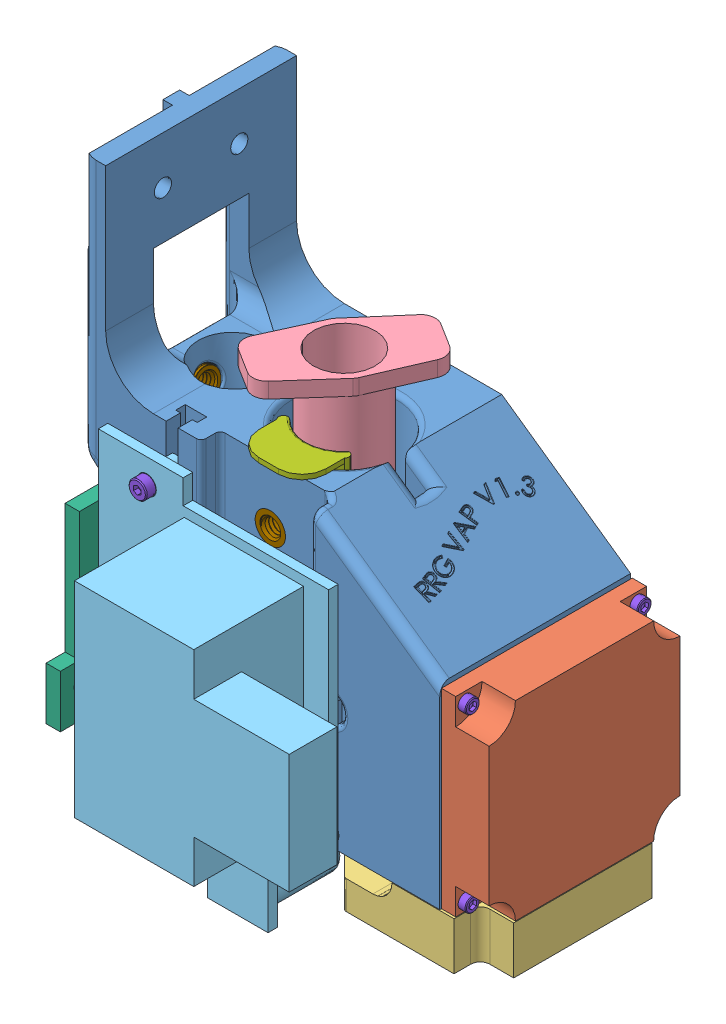
SolidWorks assembly nozzle5_assembly, configuration Default. Lengths in mm.
Overall size (89.5 117.49 68.04).
22 component instances, 9 part files, 46 mates.
Components (placement in the parent):
- nozzle5-1: nozzle5 [Default] at (-8.7686 3.4195 32.0413) size (79.5 100 40.07)
- fan-1: fan [Default] at (61.2314 3.4195 71.6933) x (0 0 -1) z (0 -1 0) size (40 10 40)
- fan_flow-1: fan_flow [Default] at (71.2314 -6.7344 72.0413) x (-1 0 0) z (0 0 -1) size (42.01 10.01 40)
- syringe_OG-1: syringe_OG [Default] at (23.2314 2.7419 54.0413) x (0.847098 0 0.531436) z (-0.531436 0 0.847098) size (15.68 90.3 30.7)
- sensing_board-1: sensing_board [Default] at (-5.6177 59.601 74.7313) x (0 -1 0) z (-1 0 0) size (73.67 39.39 63)
- heater_board-1: heater_board [Default] at (-11.7686 40.4195 78.5413) x (0 0 -1) z (-1 0 0) size (39 38 6)
- syringe_clamp_V2-1: syringe_clamp_V2 [Default] at (23.2314 13.4195 54.0413) x (0.707107 0 0.707107) z (-0.707107 0 0.707107) size (15.16 51.07 15.16)
- socket head cap screw_am-5: socket head cap screw_am [B18.3.1M - 2.5 x 0.45 x 10 Hex SHCS -- 10NHX] at (-17.2686 35.4195 68.0413) size (12.5 4.5 4.5)
- socket head cap screw_am-6: socket head cap screw_am [B18.3.1M - 2.5 x 0.45 x 10 Hex SHCS -- 10NHX] at (-17.2686 9.0195 53.1413) size (12.5 4.5 4.5)
- socket head cap screw_am-8: socket head cap screw_am [B18.3.1M - 2 x 0.4 x 10 Hex SHCS -- 10NHX] at (4.5423 54.521 78.7313) x (0 0 -1) z (1 0 0) size (12 3.8 3.8)
- socket head cap screw_am-9: socket head cap screw_am [B18.3.1M - 2 x 0.4 x 10 Hex SHCS -- 10NHX] at (4.5423 6.261 78.7313) x (0 0 -1) z (1 0 0) size (12 3.8 3.8)
- socket head cap screw_am-10: socket head cap screw_am [B18.3.1M - 2 x 0.4 x 10 Hex SHCS -- 10NHX] at (37.5623 6.261 78.7313) x (0 0 -1) z (1 0 0) size (12 3.8 3.8)
- 93365A140_HEAT-SET INSERTS FOR PLASTICS-1: 93365A140_HEAT-SET INSERTS FOR PLASTICS [93365A140] at (-10.362 55.4311 53.7913) x (0.178209 -0.977712 0.110994) z (0.019903 -0.109195 -0.993821) size (6.35 5.19 6.35)
- 93365A140_HEAT-SET INSERTS FOR PLASTICS-2: 93365A140_HEAT-SET INSERTS FOR PLASTICS [93365A140] at (-8.1205 43.1337 53.7913) x (0.178209 -0.977712 0.110994) z (0.019903 -0.109195 -0.993821) size (6.35 5.19 6.35)
- 93365A140_HEAT-SET INSERTS FOR PLASTICS-4: 93365A140_HEAT-SET INSERTS FOR PLASTICS [93365A140] at (21.7314 20.9195 68.0413) x (-0.923728 -0.383049 0) z (-0.383049 0.923728 0) size (6.35 5.19 6.35)
- 93365A140_HEAT-SET INSERTS FOR PLASTICS-5: 93365A140_HEAT-SET INSERTS FOR PLASTICS [93365A140] at (21.7314 50.9195 68.0413) x (-0.980674 -0.195651 0) z (-0.195651 0.980674 0) size (6.35 5.19 6.35)
- socket head cap screw_am-12: socket head cap screw_am [B18.3.1M - 1.6 x 0.35 x 10 Hex SHCS -- 10NHX] at (54.2314 -8.3344 69.0413) x (0 1 0) z (0 0 1) size (11.6 3 3)
- socket head cap screw_am-13: socket head cap screw_am [B18.3.1M - 1.6 x 0.35 x 10 Hex SHCS -- 10NHX] at (54.2314 -8.3344 35.0413) x (0 1 0) z (0 0 1) size (11.6 3 3)
- socket head cap screw_am-14: socket head cap screw_am [B18.3.1M - 1.6 x 0.35 x 10 Hex SHCS -- 10NHX] at (65.8314 41.4195 69.6933) x (-1 0 0) z (0 0.924225 0.381849) size (11.6 3 3)
- socket head cap screw_am-15: socket head cap screw_am [B18.3.1M - 1.6 x 0.35 x 10 Hex SHCS -- 10NHX] at (65.8314 41.4195 33.6933) x (-1 0 0) z (0 0.924225 0.381849) size (11.6 3 3)
- socket head cap screw_am-16: socket head cap screw_am [B18.3.1M - 1.6 x 0.35 x 10 Hex SHCS -- 10NHX] at (65.8314 5.4195 69.6933) x (-1 0 0) z (0 0.924225 0.381849) size (11.6 3 3)
- socket head cap screw_am-17: socket head cap screw_am [B18.3.1M - 1.6 x 0.35 x 10 Hex SHCS -- 10NHX] at (65.8314 5.4195 33.6933) x (-1 0 0) z (0 0.924225 0.381849) size (11.6 3 3)
Mates (geometry in assembly coordinates):
- Concentric1: concentric: cylinder of nozzle5-1 through (23.2314 -27.6932 54.0413) axis (0 1 0) radius 11; cylinder of syringe_OG-1 through (23.2314 74.0419 54.0413) axis (0 -1 0) radius 7.6
- Coincident2: coincident: plane of nozzle5-1 through (-8.7686 3.4195 72.0413) normal (0 -1 0); plane of fan-1 through (71.2314 3.4195 71.6933) normal (0 -1 0)
- Coincident4: coincident: plane of fan-1 through (71.2314 3.4195 71.6933) normal (1 0 0); plane of fan_flow-1 through (71.2314 -6.7344 32.0413) normal (1 0 0)
- Concentric2: concentric: cylinder of nozzle5-1 through (54.2314 13.4195 69.0413) axis (0 -1 0) radius 1.1; cylinder of fan_flow-1 through (54.2314 -6.7344 69.0413) axis (0 -1 0) radius 1.1
- Parallel1: parallel: plane of nozzle5-1 through (-8.7686 3.4195 72.0413) normal (0 0 1); plane of sensing_board-1 through (-5.6177 59.601 74.7313) normal (0 0 -1)
- Parallel2: parallel: plane of nozzle5-1 through (-8.7686 3.4195 72.0413) normal (-1 0 0); plane of sensing_board-1 through (-5.6177 59.601 76.7313) normal (-1 0 0)
- Distance1: distance = 4 mm: plane of sensing_board-1 through (23.5976 -8.9867 60.3413) normal (0 0 -1); cylinder of syringe_OG-1 through (23.2314 -13.0081 54.0413) axis (0 1 0) radius 2.3
- Parallel3: parallel: plane of nozzle5-1 through (-8.7686 3.4195 72.0413) normal (-1 0 0); plane of heater_board-1 through (-11.7686 40.4195 78.5413) normal (1 0 0)
- Concentric3: concentric: cylinder of nozzle5-1 through (23.2314 -27.6932 54.0413) axis (0 1 0) radius 11; cylinder of syringe_clamp_V2-1 through (23.2314 63.4195 54.0413) axis (0 -1 0) radius 10
- Coincident12: coincident: plane of nozzle5-1 through (61.2314 3.4195 72.0413) normal (1 0 0); plane of fan-1 through (61.2314 3.4195 71.6933) normal (-1 0 0)
- Concentric4: concentric: cylinder of nozzle5-1 through (-0.7686 35.4195 68.0413) axis (-1 0 0) radius 1.5; cylinder of heater_board-1 through (-11.7686 35.4195 68.0413) axis (-1 0 0) radius 2
- Concentric5: concentric: cylinder of nozzle5-1 through (-0.7686 9.0195 53.1413) axis (-1 0 0) radius 1.5; cylinder of heater_board-1 through (-11.7686 9.0195 53.1413) axis (-1 0 0) radius 2
- Coincident13: coincident: plane of nozzle5-1 through (-8.7686 3.4195 72.0413) normal (-1 0 0); plane of heater_board-1 through (-8.7686 9.0195 53.1413) normal (1 0 0)
- Coincident14: coincident: plane of nozzle5-1 through (-8.7686 63.4195 72.0413) normal (0 1 0); plane of syringe_clamp_V2-1 through (23.2314 63.4195 54.0413) normal (0 -1 0)
- Parallel4: parallel: plane of nozzle5-1 through (-8.7686 3.4195 68.0413) normal (0 0 1); plane of syringe_clamp_V2-1 through (23.2314 64.4195 69.9291) normal (0 0 1)
- Concentric6: concentric: cylinder of heater_board-1 through (-11.7686 35.4195 68.0413) axis (-1 0 0) radius 2; cylinder of socket head cap screw_am-5 through (-49.0186 35.4195 68.0413) axis (-1 0 0) radius 2.25
- Coincident16: coincident: plane of heater_board-1 through (-14.7686 40.4195 78.5413) normal (-1 0 0); plane of socket head cap screw_am-5 through (-14.7686 37.6695 68.0413) normal (1 0 0)
- Concentric7: concentric: cylinder of heater_board-1 through (-11.7686 9.0195 53.1413) axis (-1 0 0) radius 2; cylinder of socket head cap screw_am-6 through (-49.0186 9.0195 53.1413) axis (-1 0 0) radius 2.25
- Coincident17: coincident: plane of heater_board-1 through (-14.7686 40.4195 78.5413) normal (-1 0 0); plane of socket head cap screw_am-6 through (-14.7686 11.2695 53.1413) normal (1 0 0)
- Concentric8: concentric: cylinder of sensing_board-1 through (4.5423 54.521 76.7313) axis (0 0 -1) radius 2; cylinder of socket head cap screw_am-8 through (4.5423 54.521 110.4813) axis (0 0 1) radius 1.9
- Coincident18: coincident: plane of sensing_board-1 through (-5.6177 59.601 76.7313) normal (0 0 1); plane of socket head cap screw_am-8 through (4.5423 56.421 76.7313) normal (0 0 -1)
- Concentric9: concentric: cylinder of sensing_board-1 through (4.5423 6.261 76.7313) axis (0 0 -1) radius 2; cylinder of socket head cap screw_am-9 through (4.5423 6.261 110.4813) axis (0 0 1) radius 1.9
- Coincident19: coincident: plane of sensing_board-1 through (-5.6177 59.601 76.7313) normal (0 0 1); plane of socket head cap screw_am-9 through (4.5423 8.161 76.7313) normal (0 0 -1)
- Concentric10: concentric: cylinder of sensing_board-1 through (37.5623 6.261 76.7313) axis (0 0 -1) radius 2; cylinder of socket head cap screw_am-10 through (37.5623 6.261 110.4813) axis (0 0 1) radius 1.9
- Coincident20: coincident: plane of sensing_board-1 through (-5.6177 59.601 76.7313) normal (0 0 1); plane of socket head cap screw_am-10 through (37.5623 8.161 76.7313) normal (0 0 -1)
- Concentric11: concentric: cone of nozzle5-1 through (21.7314 50.9195 72.0413) axis (0 0 -1); cylinder of 93365A140_HEAT-SET INSERTS FOR PLASTICS-5 through (21.7314 50.9195 68.0413) axis (0 0 1) radius 2.921
- Coincident21: coincident: plane of nozzle5-1 through (-8.7686 3.4195 68.0413) normal (0 0 1); plane of 93365A140_HEAT-SET INSERTS FOR PLASTICS-5 through (21.7314 50.9195 68.0413) normal (0 0 1)
- Coincident22: coincident: plane of nozzle5-1 through (-8.7686 3.4195 68.0413) normal (0 0 1); plane of 93365A140_HEAT-SET INSERTS FOR PLASTICS-4 through (21.7314 20.9195 68.0413) normal (0 0 1)
- Concentric12: concentric: cone of nozzle5-1 through (21.7314 20.9195 72.0413) axis (0 0 -1); cylinder of 93365A140_HEAT-SET INSERTS FOR PLASTICS-4 through (21.7314 20.9195 68.0413) axis (0 0 1) radius 2.921
- Coincident23: coincident: plane of nozzle5-1 through (-1.1354 4.8108 32.0413) normal (-0.983791 -0.179317 0); plane of 93365A140_HEAT-SET INSERTS FOR PLASTICS-1 through (-10.362 55.4311 53.7913) normal (-0.983791 -0.179317 0)
- Coincident24: coincident: plane of nozzle5-1 through (-1.1354 4.8108 32.0413) normal (-0.983791 -0.179317 0); circle of 93365A140_HEAT-SET INSERTS FOR PLASTICS-2
- Concentric13: concentric: circle of nozzle5-1; circle of 93365A140_HEAT-SET INSERTS FOR PLASTICS-1
- Concentric14: concentric: circle of nozzle5-1; circle of 93365A140_HEAT-SET INSERTS FOR PLASTICS-2
- Parallel5: parallel: plane of nozzle5-1 through (2.9114 -3.3073 67.0413) normal (0 0 1); plane of socket head cap screw_am-8 through (4.5423 55.295 66.7313) normal (0 0 -1)
- Concentric15: concentric: cylinder of fan_flow-1 through (54.2314 -6.7344 69.0413) axis (0 -1 0) radius 2.2; cylinder of socket head cap screw_am-12 through (54.2314 -40.0844 69.0413) axis (0 -1 0) radius 1.5
- Coincident28: coincident: plane of fan_flow-1 through (71.2314 -6.7344 32.0413) normal (0 -1 0); plane of socket head cap screw_am-12 through (52.7314 -6.7344 69.0413) normal (0 1 0)
- Concentric16: concentric: cylinder of fan_flow-1 through (54.2314 -6.7344 35.0413) axis (0 -1 0) radius 2.2; cylinder of socket head cap screw_am-13 through (54.2314 -40.0844 35.0413) axis (0 -1 0) radius 1.5
- Coincident29: coincident: plane of fan_flow-1 through (71.2314 -6.7344 32.0413) normal (0 -1 0); plane of socket head cap screw_am-13 through (52.7314 -6.7344 35.0413) normal (0 1 0)
- Concentric17: concentric: cylinder of fan-1 through (71.2314 41.4195 69.6933) axis (-1 0 0) radius 1.1; cylinder of socket head cap screw_am-14 through (97.5814 41.4195 69.6933) axis (1 0 0) radius 1.5
- Coincident30: coincident: plane of fan-1 through (64.2314 43.4195 71.6933) normal (1 0 0); plane of socket head cap screw_am-14 through (64.2314 40.8467 71.0796) normal (-1 0 0)
- Concentric18: concentric: cylinder of fan-1 through (71.2314 41.4195 33.6933) axis (-1 0 0) radius 1.1; cylinder of socket head cap screw_am-15 through (97.5814 41.4195 33.6933) axis (1 0 0) radius 1.5
- Coincident31: coincident: plane of fan-1 through (64.2314 43.4195 31.6933) normal (1 0 0); plane of socket head cap screw_am-15 through (64.2314 40.8467 35.0796) normal (-1 0 0)
- Concentric19: concentric: cylinder of fan-1 through (71.2314 5.4195 69.6933) axis (-1 0 0) radius 1.1; cylinder of socket head cap screw_am-16 through (97.5814 5.4195 69.6933) axis (1 0 0) radius 1.5
- Coincident32: coincident: plane of fan-1 through (64.2314 3.4195 71.6933) normal (1 0 0); plane of socket head cap screw_am-16 through (64.2314 4.8467 71.0796) normal (-1 0 0)
- Concentric20: concentric: cylinder of fan-1 through (71.2314 5.4195 33.6933) axis (-1 0 0) radius 1.1; cylinder of socket head cap screw_am-17 through (97.5814 5.4195 33.6933) axis (1 0 0) radius 1.5
- Coincident33: coincident: plane of fan-1 through (64.2314 3.4195 31.6933) normal (1 0 0); plane of socket head cap screw_am-17 through (64.2314 4.8467 35.0796) normal (-1 0 0)
